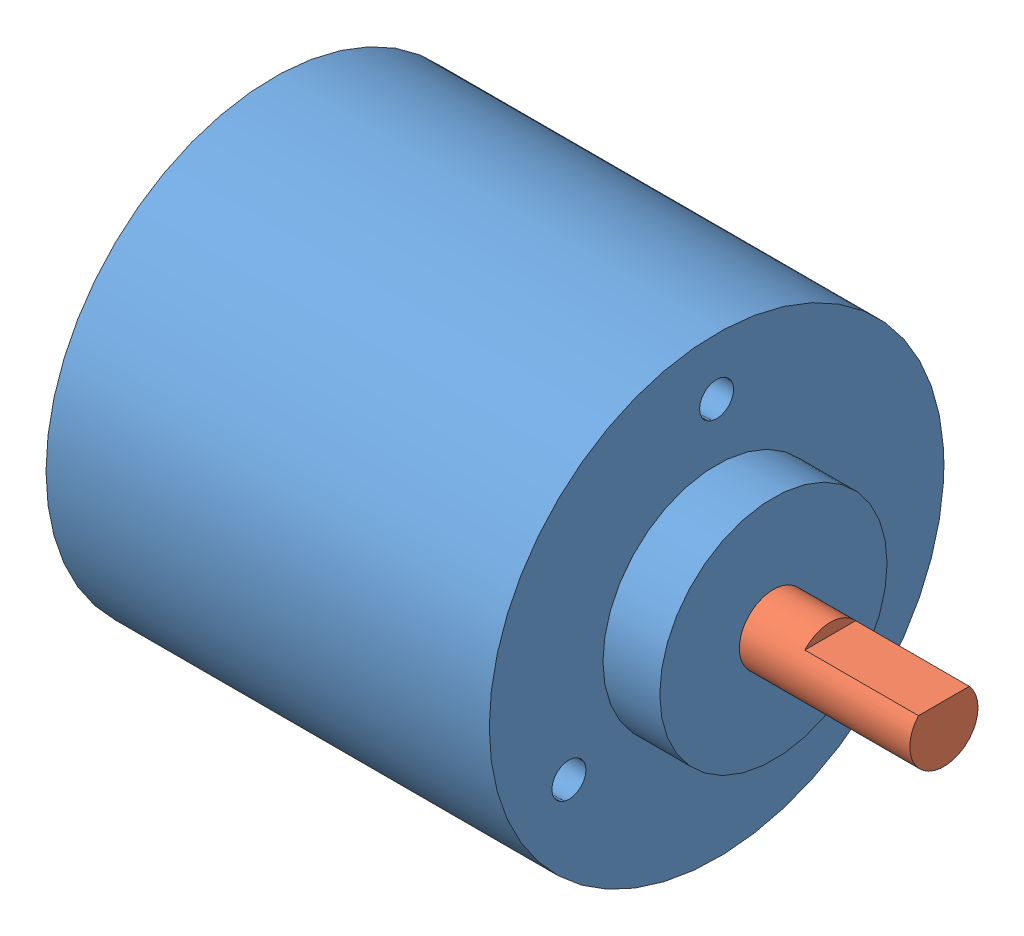
SolidWorks assembly enkoder-1, configuration Varsayılan. Lengths in mm.
Overall size (59 40 40).
2 component instances, 2 part files, 2 mates.
Components (placement in the parent):
- enkoder-1: enkoder [Varsayılan] at (-37.2093 2.4478 44) size (44 40 40)
- enkoder-mil-1: enkoder-mil [Varsayılan] at (1.7907 2.4478 44) size (20 6 6)
Mates (geometry in assembly coordinates):
- Concentric1: concentric aligned: circle of enkoder-1; circle of enkoder-mil-1
- Distance1: distance = 0 mm anti-aligned: plane of enkoder-mil-1 through (1.7907 2.4478 44) normal (-1 0 0); plane of enkoder-1 through (1.7907 2.4478 44) normal (1 0 0)
